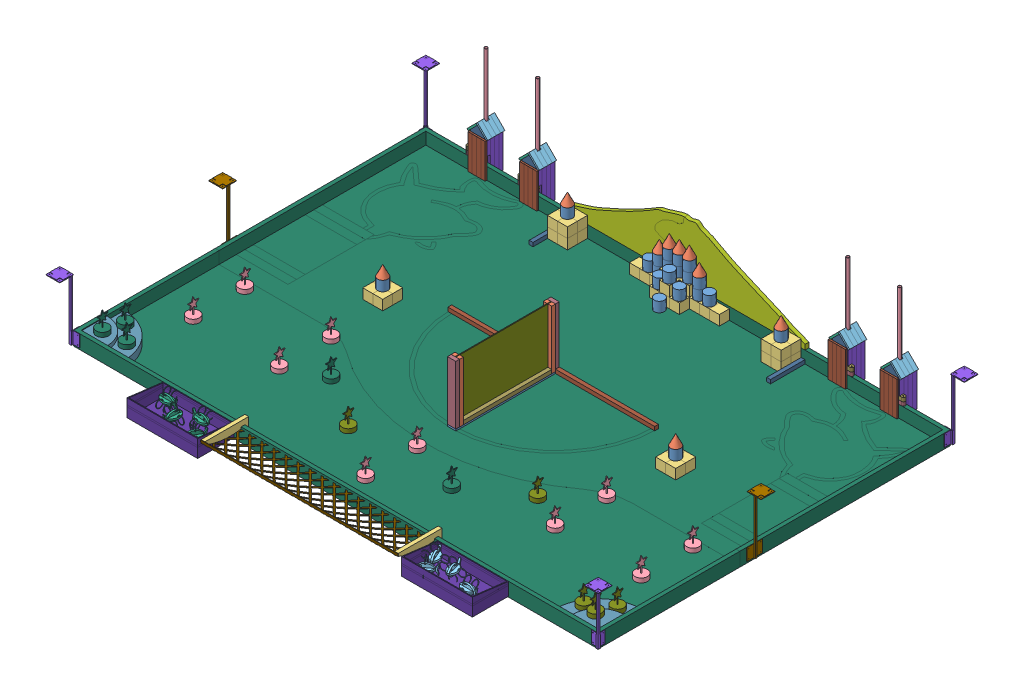
SolidWorks assembly ASSY Table with elements, configuration Défaut. Lengths in mm.
Overall size (3204 625.51 2355.54).
175 component instances, 34 part files, 0 mates.
Components (placement in the parent):
- Sand Cylinder-1: Sand Cylinder [Défaut] at (-202.9619 -789.2121 -1160.7894) x (0.242681 0 0.970106) z (-0.970106 0 0.242681) size (58 58 58)
- Sand Cylinder-2: Sand Cylinder [Défaut] at (-144.9619 -789.2121 -1160.7888) x (0.242681 0 0.970106) z (-0.970106 0 0.242681) size (58 58 58)
- Sand Cylinder-3: Sand Cylinder [Défaut] at (-86.9619 -789.2121 -1160.7881) x (0.242681 0 0.970106) z (-0.970106 0 0.242681) size (58 58 58)
- Sand Cylinder-4: Sand Cylinder [Défaut] at (-764.9619 -847.2121 -1131.7894) x (0.221056 0 -0.975261) z (0.975261 0 0.221056) size (58 58 58)
- Sand Cone-1: Sand Cone [Défaut] at (-764.9619 -818.2121 -1131.7894) size (58 60 58)
- Sand Cylinder-5: Sand Cylinder [Défaut] at (475.0381 -847.2121 -1131.7894) x (0.221056 0 -0.975261) z (0.975261 0 0.221056) size (58 58 58)
- Sand Cone-2: Sand Cone [Défaut] at (475.0381 -818.2121 -1131.7894) size (58 60 58)
- Sand Cube-1: Sand Cube [Défaut] at (-793.9619 -963.2121 -1160.7894) x (1 0 0) z (0 0 -1) size (58 58 58)
- Sand Cube-2: Sand Cube [Défaut] at (-793.9619 -963.2121 -1102.7894) x (1 0 0) z (0 0 -1) size (58 58 58)
- Sand Cube-3: Sand Cube [Défaut] at (-735.9619 -963.2121 -1160.7894) x (1 0 0) z (0 0 -1) size (58 58 58)
- Sand Cube-4: Sand Cube [Défaut] at (-735.9619 -963.2121 -1102.7894) x (1 0 0) z (0 0 -1) size (58 58 58)
- Sand Cube-5: Sand Cube [Défaut] at (-793.9619 -905.2121 -1160.7894) x (1 0 0) z (0 0 -1) size (58 58 58)
- Sand Cube-6: Sand Cube [Défaut] at (-793.9619 -905.2121 -1102.7894) x (1 0 0) z (0 0 -1) size (58 58 58)
- Sand Cube-7: Sand Cube [Défaut] at (-735.9619 -905.2121 -1160.7894) x (1 0 0) z (0 0 -1) size (58 58 58)
- Sand Cube-8: Sand Cube [Défaut] at (-735.9619 -905.2121 -1102.7894) x (1 0 0) z (0 0 -1) size (58 58 58)
- Sand Cube-9: Sand Cube [Défaut] at (446.0381 -963.2121 -1160.7894) x (1 0 0) z (0 0 -1) size (58 58 58)
- Sand Cube-10: Sand Cube [Défaut] at (446.0381 -963.2121 -1102.7894) x (1 0 0) z (0 0 -1) size (58 58 58)
- Sand Cube-11: Sand Cube [Défaut] at (504.0381 -963.2121 -1160.7894) x (1 0 0) z (0 0 -1) size (58 58 58)
- Sand Cube-12: Sand Cube [Défaut] at (504.0381 -963.2121 -1102.7894) x (1 0 0) z (0 0 -1) size (58 58 58)
- Sand Cube-13: Sand Cube [Défaut] at (446.0381 -905.2121 -1160.7894) x (1 0 0) z (0 0 -1) size (58 58 58)
- Sand Cube-14: Sand Cube [Défaut] at (446.0381 -905.2121 -1102.7894) x (1 0 0) z (0 0 -1) size (58 58 58)
- Sand Cube-15: Sand Cube [Défaut] at (504.0381 -905.2121 -1160.7894) x (1 0 0) z (0 0 -1) size (58 58 58)
- Sand Cube-16: Sand Cube [Défaut] at (504.0381 -905.2121 -1102.7894) x (1 0 0) z (0 0 -1) size (58 58 58)
- Seashell-1: Seashell [Défaut] at (-944.9619 -992.2221 60.2106) size (72 112 72)
- Seashell-2: Seashell [Défaut] at (-944.9619 -992.2221 360.2106) size (72 112 72)
- Seashell-3: Seashell [Défaut] at (655.0381 -992.2221 60.2106) size (72 112 72)
- Seashell-4: Seashell [Défaut] at (655.0381 -992.2221 360.2106) size (72 112 72)
- Fish Green-1: Fish Green [Défaut] at (717.4358 -937.2221 972.1941) size (97.04 131 131)
- Fish Green-2: Fish Green [Défaut] at (631.9848 -937.2221 959.6309) x (-0.234784 0 -0.972048) z (0.972048 0 -0.234784) size (97.04 131 131)
- Fish Green-3: Fish Green [Défaut] at (501.1179 -937.2221 1014.7557) x (0.812367 0 -0.583146) z (-0.583146 0 -0.812367) size (97.04 131 131)
- Fish Green-4: Fish Green [Défaut] at (522.5335 -937.2221 944.1684) x (-0.397901 0 -0.917428) z (0.917428 0 -0.397901) size (97.04 131 131)
- Fish Violet-1: Fish Violet [Défaut] at (-957.2835 -937.2221 913.1703) x (-0.109408 0 0.993997) z (0.993997 0 0.109408) size (97.04 131 131)
- Fish Violet-2: Fish Violet [Défaut] at (-1103.3076 -937.2221 894.5357) size (97.04 131 131)
- Fish Violet-3: Fish Violet [Défaut] at (-824.2077 -937.2221 1029.6158) x (0.500245 0 -0.865884) z (0.865884 0 0.500245) size (97.04 131 131)
- Fish Violet-4: Fish Violet [Défaut] at (-820.6321 -937.2221 897.2149) x (-0.995132 0 -0.098547) z (-0.098547 0 0.995132) size (97.04 131 131)
- ASSY Table-1: ASSY Table [Défaut] at (-1644.9619 -992.2121 -1189.7894) size (3204 625 2340.46)
  - arc-1: arc [Défaut] at (1500 70 -22) size (1400 364.44 22)
  - Beacon support corner-1: Beacon support corner [Défaut] x (0 0 -1) z (1 0 0) size (117 352 117)
  - Beacon support corner-2: Beacon support corner [Défaut] at (3000 0 0) size (117 352 117)
  - Beacon support corner-3: Beacon support corner [Défaut] at (0 0 2000) x (-1 0 0) z (0 0 -1) size (117 352 117)
  - Beacon support corner-4: Beacon support corner [Défaut] at (3000 0 2000) x (0 0 1) z (-1 0 0) size (117 352 117)
  - Beacon support middle-1: Beacon support middle [Défaut] at (0 0 1157) x (0 0 -1) z (1 0 0) size (90 352 80)
  - Beacon support middle-2: Beacon support middle [Défaut] at (3000 0 1077) x (0 0 1) z (-1 0 0) size (90 352 80)
  - Rod 1-1: Rod 1 [Défaut] at (2189 11 0) x (0 -1 0) z (0 0 1) size (22 22 200)
  - Rod 1-2: Rod 1 [Défaut] at (811 11 0) x (0 1 0) z (0 0 1) size (22 22 200)
  - Rod 2-1: Rod 2 [Défaut] at (900 11 761) x (0 0 1) z (1 0 0) size (22 22 576)
  - Rod 2-2: Rod 2 [Défaut] at (1524 11 761) x (0 1 0) z (1 0 0) size (22 22 576)
  - Rod 3-1: Rod 3 [Défaut] at (1486.5 21 1306) x (1 0 0) z (0 0 -1) size (22 22 512)
  - Rod 3-2: Rod 3 [Défaut] at (1513.5 21 1306) x (1 0 0) z (0 0 -1) size (22 22 512)
  - Rod 4-1: Rod 4 [Défaut] at (1499.5 350 1339) x (1 0 0) z (0 -1 0) size (48 22 340)
  - Rod 4-2: Rod 4 [Défaut] at (1500 350 761) x (1 0 0) z (0 -1 0) size (48 22 340)
  - Round border-1: Round border [Défaut] at (-0.01 -0.01 2000) x (-1 0 0) z (0 0 -1) size (250 66 250)
  - Round border-2: Round border [Défaut] at (3000.01 -0.01 2000) x (0 0 1) z (-1 0 0) size (250 66 250)
  - Table-1: Table [Défaut] at (3022 0 2022) size (3044 80 2044)
  - Glass-1: Glass [Défaut] at (1500 10 772) x (0 0 1) z (-1 0 0) size (556 340 5)
  - Aquarium-1: Aquarium [Défaut] at (703.01 -5.01 2127) x (0 0 1) z (-1 0 0) size (210 100 410)
  - Aquarium-2: Aquarium [Défaut] at (2296.99 -5.01 2127) x (0 0 1) z (-1 0 0) size (210 100 410)
  - Net-1: Net [Défaut] at (2072 72.3659 2127.7617) x (0 0.120229 0.992746) z (-1 0 0) size (214.07 31.72 1144)
  - Rod 7-1: Rod 7 [Défaut] at (1500 5 750) size (48 10 600)
  - Rod 8-1: Rod 8 [Défaut] at (1513.5 350 1317) x (1 0 0) z (0 -1 0) size (22 22 340)
  - Rod 8-2: Rod 8 [Défaut] at (1486.5 350 1317) x (1 0 0) z (0 -1 0) size (22 22 340)
  - Rod 8-3: Rod 8 [Défaut] at (1486.5 350 783) x (-1 0 0) z (0 -1 0) size (22 22 340)
  - Rod 8-4: Rod 8 [Défaut] at (1513.5 350 783) x (1 0 0) z (0 -1 0) size (22 22 340)
  - Net Support-1: Net Support [Défaut] at (950 -0.01 1978) x (0 0 1) z (-1 0 0) size (254 100 22)
  - Net Support-2: Net Support [Défaut] at (2072 -0.01 1978) x (0 0 1) z (-1 0 0) size (254 100 22)
  - Beach Hut Green-1: Beach Hut Green [Défaut] at (2091.5087 -11.3682 -247.8389) x (-1 0 0) z (0 0 1) size (132.1 615 113.42)
    - Beach hut - Matt-1: Beach hut - Matt [Défaut] at (-308.4913 -626.3682 198.8389) x (-0.87546 0 0.48329) z (-0.48329 0 -0.87546) size (18 500 18)
    - Beach hut - Roof 2-1: Beach hut - Roof 2 [Défaut] at (-338.5433 -245.4583 161.3389) x (0 0 1) z (-0.707107 0.707107 0) size (100 10 85)
    - Beach hut - Roof 1-1: Beach hut - Roof 1 [Défaut] at (-281.9748 -234.8517 161.3389) x (0 0 1) z (0.707107 0.707107 0) size (100 10 75)
    - Beach hut - Wall 1-1: Beach hut - Wall 1 [Défaut] at (-258.4913 -116.3682 161.3389) x (0 0 1) z (0 -1 0) size (100 10 210)
    - Beach hut - Wall 2-1: Beach hut - Wall 2 [Défaut] at (-358.4913 -116.3682 161.3389) x (0 0 1) z (0 -1 0) size (100 10 210)
    - Beach hut - Wall back-1: Beach hut - Wall back [Défaut] at (-308.4913 -161.3682 148.8389) x (-1 0 0) z (0 0 1) size (80 100 10)
    - Beach hut - Wall front-1: Beach hut - Wall front [Défaut] at (-308.4913 -126.3682 238.8389) x (-1 0 0) z (0 0 1) size (80 135 10)
    - Beach hut - door-1: Beach hut - door [Défaut] at (-340.9913 -112.3682 258.8389) x (1 0 0) z (0 1 0) size (100 10 200)
    - Beach hut - Ground-1: Beach hut - Ground [Défaut] at (-308.4913 -126.3682 198.8389) size (112 22 100)
    - Beach hut - Door 2-1: Beach hut - Door 2 [Défaut] at (-369.4913 -82.3682 237.8389) x (0 0 1) z (1 0 0) size (103.42 22 106)
    - Beach hut - Wall 3-1: Beach hut - Wall 3 [Défaut] at (-308.4913 -81.3682 215.8389) size (80 70 10)
  - Beach Hut Green_1-1: Beach Hut Green_1 [Défaut] at (2391.5087 -11.3682 -247.8389) x (-1 0 0) z (0 0 1) size (132.1 615 113.42)
    - Beach hut - Wall 1-1: Beach hut - Wall 1 [Défaut] at (-258.4913 -116.3682 161.3389) x (0 0 1) z (0 -1 0) size (100 10 210)
    - Beach hut - Wall 2-1: Beach hut - Wall 2 [Défaut] at (-358.4913 -116.3682 161.3389) x (0 0 1) z (0 -1 0) size (100 10 210)
    - Beach hut - Wall back-1: Beach hut - Wall back [Défaut] at (-308.4913 -161.3682 148.8389) x (-1 0 0) z (0 0 1) size (80 100 10)
    - Beach hut - Wall front-1: Beach hut - Wall front [Défaut] at (-308.4913 -126.3682 238.8389) x (-1 0 0) z (0 0 1) size (80 135 10)
    - Beach hut - door-1: Beach hut - door [Défaut] at (-340.9913 -112.3682 258.8389) x (1 0 0) z (0 1 0) size (100 10 200)
    - Beach hut - Ground-1: Beach hut - Ground [Défaut] at (-308.4913 -126.3682 198.8389) size (112 22 100)
    - Beach hut - Door 2-1: Beach hut - Door 2 [Défaut] at (-369.4913 -82.3682 237.8389) x (0 0 1) z (1 0 0) size (103.42 22 106)
    - Beach hut - Wall 3-1: Beach hut - Wall 3 [Défaut] at (-308.4913 -81.3682 215.8389) size (80 70 10)
    - Beach hut - Matt-1: Beach hut - Matt [Défaut] at (-308.4913 -626.3682 198.8389) x (-0.87546 0 0.48329) z (-0.48329 0 -0.87546) size (18 500 18)
    - Beach hut - Roof 2-1: Beach hut - Roof 2 [Défaut] at (-338.5433 -245.4583 161.3389) x (0 0 1) z (-0.707107 0.707107 0) size (100 10 85)
    - Beach hut - Roof 1-1: Beach hut - Roof 1 [Défaut] at (-281.9748 -234.8517 161.3389) x (0 0 1) z (0.707107 0.707107 0) size (100 10 75)
  - Beach Hut Violet-1: Beach Hut Violet [Défaut] at (291.5087 -11.3682 -247.8389) x (-1 0 0) z (0 0 1) size (132.1 615 113.42)
    - Beach hut - Matt-1: Beach hut - Matt [Défaut] at (-308.4913 -626.3682 198.8389) x (-0.87546 0 0.48329) z (-0.48329 0 -0.87546) size (18 500 18)
    - Beach hut - Roof 2-1: Beach hut - Roof 2 [Défaut] at (-338.5433 -245.4583 161.3389) x (0 0 1) z (-0.707107 0.707107 0) size (100 10 85)
    - Beach hut - Roof 1-1: Beach hut - Roof 1 [Défaut] at (-281.9748 -234.8517 161.3389) x (0 0 1) z (0.707107 0.707107 0) size (100 10 75)
    - Beach hut - Wall 1-1: Beach hut - Wall 1 [Défaut] at (-258.4913 -116.3682 161.3389) x (0 0 1) z (0 -1 0) size (100 10 210)
    - Beach hut - Wall 2-1: Beach hut - Wall 2 [Défaut] at (-358.4913 -116.3682 161.3389) x (0 0 1) z (0 -1 0) size (100 10 210)
    - Beach hut - Wall back-1: Beach hut - Wall back [Défaut] at (-308.4913 -161.3682 148.8389) x (-1 0 0) z (0 0 1) size (80 100 10)
    - Beach hut - Wall front-1: Beach hut - Wall front [Défaut] at (-308.4913 -126.3682 238.8389) x (-1 0 0) z (0 0 1) size (80 135 10)
    - Beach hut - door-1: Beach hut - door [Défaut] at (-275.9913 -112.3682 248.8389) x (-1 0 0) z (0 1 0) size (100 10 200)
    - Beach hut - Door 2-1: Beach hut - Door 2 [Défaut] at (-247.4913 -104.3682 237.8389) x (0 0 1) z (-1 0 0) size (103.42 22 106)
    - Beach hut - Wall 3-1: Beach hut - Wall 3 [Défaut] at (-308.4913 -81.3682 215.8389) size (80 70 10)
    - Beach hut - Ground-1: Beach hut - Ground [Défaut] at (-308.4913 -104.3682 198.8389) x (-1 0 0) z (0 0 1) size (112 22 100)
  - Beach Hut Violet_1-1: Beach Hut Violet_1 [Défaut] at (-8.4913 -11.3682 -247.8389) x (-1 0 0) z (0 0 1) size (132.1 615 113.42)
    - Beach hut - Matt-1: Beach hut - Matt [Défaut] at (-308.4913 -626.3682 198.8389) x (-0.87546 0 0.48329) z (-0.48329 0 -0.87546) size (18 500 18)
    - Beach hut - Roof 2-1: Beach hut - Roof 2 [Défaut] at (-338.5433 -245.4583 161.3389) x (0 0 1) z (-0.707107 0.707107 0) size (100 10 85)
    - Beach hut - Roof 1-1: Beach hut - Roof 1 [Défaut] at (-281.9748 -234.8517 161.3389) x (0 0 1) z (0.707107 0.707107 0) size (100 10 75)
    - Beach hut - Wall 1-1: Beach hut - Wall 1 [Défaut] at (-258.4913 -116.3682 161.3389) x (0 0 1) z (0 -1 0) size (100 10 210)
    - Beach hut - Wall 2-1: Beach hut - Wall 2 [Défaut] at (-358.4913 -116.3682 161.3389) x (0 0 1) z (0 -1 0) size (100 10 210)
    - Beach hut - Wall back-1: Beach hut - Wall back [Défaut] at (-308.4913 -161.3682 148.8389) x (-1 0 0) z (0 0 1) size (80 100 10)
    - Beach hut - Wall front-1: Beach hut - Wall front [Défaut] at (-308.4913 -126.3682 238.8389) x (-1 0 0) z (0 0 1) size (80 135 10)
    - Beach hut - door-1: Beach hut - door [Défaut] at (-275.9913 -112.3682 248.8389) x (-1 0 0) z (0 1 0) size (100 10 200)
    - Beach hut - Door 2-1: Beach hut - Door 2 [Défaut] at (-247.4913 -104.3682 237.8389) x (0 0 1) z (-1 0 0) size (103.42 22 106)
    - Beach hut - Wall 3-1: Beach hut - Wall 3 [Défaut] at (-308.4913 -81.3682 215.8389) size (80 70 10)
    - Beach hut - Ground-1: Beach hut - Ground [Défaut] at (-308.4913 -104.3682 198.8389) x (-1 0 0) z (0 0 1) size (112 22 100)
- Sand Cone-3: Sand Cone [Défaut] at (-260.9619 -818.2121 -1160.7894) size (58 60 58)
- Sand Cone-4: Sand Cone [Défaut] at (-202.9619 -760.2121 -1160.7894) x (0.242681 0 0.970106) z (-0.970106 0 0.242681) size (58 60 58)
- Sand Cone-5: Sand Cone [Défaut] at (-144.9619 -760.2121 -1160.7888) x (0.945583 0 0.325381) z (-0.325381 0 0.945583) size (58 60 58)
- Sand Cone-6: Sand Cone [Défaut] at (-86.9619 -760.2121 -1160.7881) size (58 60 58)
- Sand Cone-7: Sand Cone [Défaut] at (-28.9619 -818.2121 -1160.7894) size (58 60 58)
- Sand Cube-17: Sand Cube [Défaut] at (-144.9619 -905.2121 -1102.7894) x (1 0 0) z (0 -1 0) size (58 58 58)
- Sand Cylinder-6: Sand Cylinder [Défaut] at (-144.9619 -847.2121 -1102.7894) size (58 58 58)
- Sand Cylinder-7: Sand Cylinder [Défaut] at (-144.9619 -963.2121 -1044.7894) size (58 58 58)
- Sand Cylinder-8: Sand Cylinder [Défaut] at (-202.9619 -905.2121 -1102.7894) size (58 58 58)
- Sand Cylinder-9: Sand Cylinder [Défaut] at (-86.9619 -905.2121 -1102.7894) size (58 58 58)
- Seashell Violet-1: Seashell Violet [Défaut] at (155.0381 -992.2221 460.2106) size (72 112 72)
- Seashell Violet-2: Seashell Violet [Défaut] at (-744.9619 -992.2221 260.2106) size (72 112 72)
- Seashell Violet-3: Seashell Violet [Défaut] at (-1466.0661 -948.2221 724.9064) size (72 112 72)
- Seashell Violet-4: Seashell Violet [Défaut] at (-1576.5512 -926.2221 755.4177) size (72 112 72)
- Sand Cylinder-10: Sand Cylinder [Défaut] at (-994.9619 -905.2121 -289.7894) x (0.98653 0 0.163577) z (-0.163577 0 0.98653) size (58 58 58)
- Sand Cone-8: Sand Cone [Défaut] at (-994.9619 -876.2121 -289.7894) x (0.086696 0 0.996235) z (-0.996235 0 0.086696) size (58 60 58)
- Sand Cylinder-11: Sand Cylinder [Défaut] at (705.0381 -905.2121 -289.7894) x (0.98653 0 0.163577) z (-0.163577 0 0.98653) size (58 58 58)
- Sand Cone-9: Sand Cone [Défaut] at (705.0381 -876.2121 -289.7894) x (0.086696 0 0.996235) z (-0.996235 0 0.086696) size (58 60 58)
- Sand Cube-18: Sand Cube [Défaut] at (-1023.9619 -963.2121 -260.7894) x (0 0 -1) z (1 0 0) size (58 58 58)
- Sand Cube-19: Sand Cube [Défaut] at (-965.9619 -963.2121 -260.7894) x (0 0 -1) z (1 0 0) size (58 58 58)
- Sand Cube-20: Sand Cube [Défaut] at (-1023.9619 -963.2121 -318.7894) x (0 0 -1) z (1 0 0) size (58 58 58)
- Sand Cube-21: Sand Cube [Défaut] at (-965.9619 -963.2121 -318.7894) x (0 0 -1) z (1 0 0) size (58 58 58)
- Sand Cube-22: Sand Cube [Défaut] at (676.0381 -963.2121 -260.7894) x (0 0 -1) z (1 0 0) size (58 58 58)
- Sand Cube-23: Sand Cube [Défaut] at (734.0381 -963.2121 -260.7894) x (0 0 -1) z (1 0 0) size (58 58 58)
- Sand Cube-24: Sand Cube [Défaut] at (676.0381 -963.2121 -318.7894) x (0 0 -1) z (1 0 0) size (58 58 58)
- Sand Cube-25: Sand Cube [Défaut] at (734.0381 -963.2121 -318.7894) x (0 0 -1) z (1 0 0) size (58 58 58)
- Seashell Violet-5: Seashell Violet [Défaut] at (-1569.0642 -948.2221 629.9961) size (72 112 72)
- Seashell Green-1: Seashell Green [Défaut] at (455.0381 -992.2221 260.2106) size (72 112 72)
- Seashell-5: Seashell [Défaut] at (-1444.9619 -992.2221 360.2106) size (72 112 72)
- Seashell-6: Seashell [Défaut] at (-144.9619 -992.2221 360.2106) size (72 112 72)
- Seashell-7: Seashell [Défaut] at (-1444.9619 -992.2221 60.2106) size (72 112 72)
- Seashell-8: Seashell [Défaut] at (1155.0381 -992.2221 60.2106) size (72 112 72)
- Seashell-9: Seashell [Défaut] at (1155.0381 -992.2221 360.2106) size (72 112 72)
- Seashell-10: Seashell [Défaut] at (-144.9619 -992.2221 660.2106) size (72 112 72)
- Seashell Green-2: Seashell Green [Défaut] at (1287.2783 -948.2221 630.0443) size (72 112 72)
- Seashell Green-3: Seashell Green [Défaut] at (1172.5052 -948.2221 711.3299) size (72 112 72)
- Seashell Green-4: Seashell Green [Défaut] at (1270.6904 -926.2221 740.7283) size (72 112 72)
- Seashell Green-5: Seashell Green [Défaut] at (-444.9619 -992.2221 460.2106) size (72 112 72)
- Sand Cube-26: Sand Cube [Défaut] at (-376.9619 -963.2121 -1160.7894) x (1 0 0) z (0 -1 0) size (58 58 58)
- Sand Cube-27: Sand Cube [Défaut] at (-318.9619 -963.2121 -1160.7894) x (1 0 0) z (0 -1 0) size (58 58 58)
- Sand Cube-28: Sand Cube [Défaut] at (-260.9619 -963.2121 -1160.7894) x (1 0 0) z (0 -1 0) size (58 58 58)
- Sand Cube-29: Sand Cube [Défaut] at (-202.9619 -963.2121 -1160.7894) x (1 0 0) z (0 -1 0) size (58 58 58)
- Sand Cube-30: Sand Cube [Défaut] at (-144.9619 -963.2121 -1160.7894) x (1 0 0) z (0 -1 0) size (58 58 58)
- Sand Cube-31: Sand Cube [Défaut] at (-86.9619 -963.2121 -1160.7894) x (1 0 0) z (0 -1 0) size (58 58 58)
- Sand Cube-32: Sand Cube [Défaut] at (-28.9619 -963.2121 -1160.7894) x (1 0 0) z (0 -1 0) size (58 58 58)
- Sand Cube-33: Sand Cube [Défaut] at (29.0381 -963.2121 -1160.7894) x (1 0 0) z (0 -1 0) size (58 58 58)
- Sand Cube-34: Sand Cube [Défaut] at (87.0381 -963.2121 -1160.7894) x (1 0 0) z (0 -1 0) size (58 58 58)
- Sand Cube-35: Sand Cube [Défaut] at (-202.9619 -963.2121 -1102.7894) x (1 0 0) z (0 0 -1) size (58 58 58)
- Sand Cube-36: Sand Cube [Défaut] at (-144.9619 -963.2121 -1102.7894) x (1 0 0) z (0 0 -1) size (58 58 58)
- Sand Cube-37: Sand Cube [Défaut] at (-86.9619 -963.2121 -1102.7894) x (1 0 0) z (0 0 -1) size (58 58 58)
- Sand Cube-38: Sand Cube [Défaut] at (-202.9619 -905.2121 -1160.7894) x (1 0 0) z (0 -1 0) size (58 58 58)
- Sand Cube-39: Sand Cube [Défaut] at (-144.9619 -905.2121 -1160.7894) x (1 0 0) z (0 -1 0) size (58 58 58)
- Sand Cube-40: Sand Cube [Défaut] at (-86.9619 -905.2121 -1160.7894) x (1 0 0) z (0 -1 0) size (58 58 58)
- Sand Cylinder-12: Sand Cylinder [Défaut] at (-260.9619 -905.2121 -1160.7894) size (58 58 58)
- Sand Cylinder-13: Sand Cylinder [Défaut] at (-318.9619 -905.2121 -1160.7894) size (58 58 58)
- Sand Cylinder-14: Sand Cylinder [Défaut] at (-28.9619 -905.2121 -1160.7894) size (58 58 58)
- Sand Cylinder-15: Sand Cylinder [Défaut] at (29.0381 -905.2121 -1160.7894) size (58 58 58)
- Sand Cylinder-16: Sand Cylinder [Défaut] at (-260.9619 -847.2121 -1160.7894) size (58 58 58)
- Sand Cylinder-17: Sand Cylinder [Défaut] at (-202.9619 -847.2121 -1160.7894) size (58 58 58)
- Sand Cylinder-18: Sand Cylinder [Défaut] at (-144.9619 -847.2121 -1160.7894) size (58 58 58)
- Sand Cylinder-19: Sand Cylinder [Défaut] at (-86.9619 -847.2121 -1160.7894) size (58 58 58)
- Sand Cylinder-20: Sand Cylinder [Défaut] at (-28.9619 -847.2121 -1160.7894) size (58 58 58)
